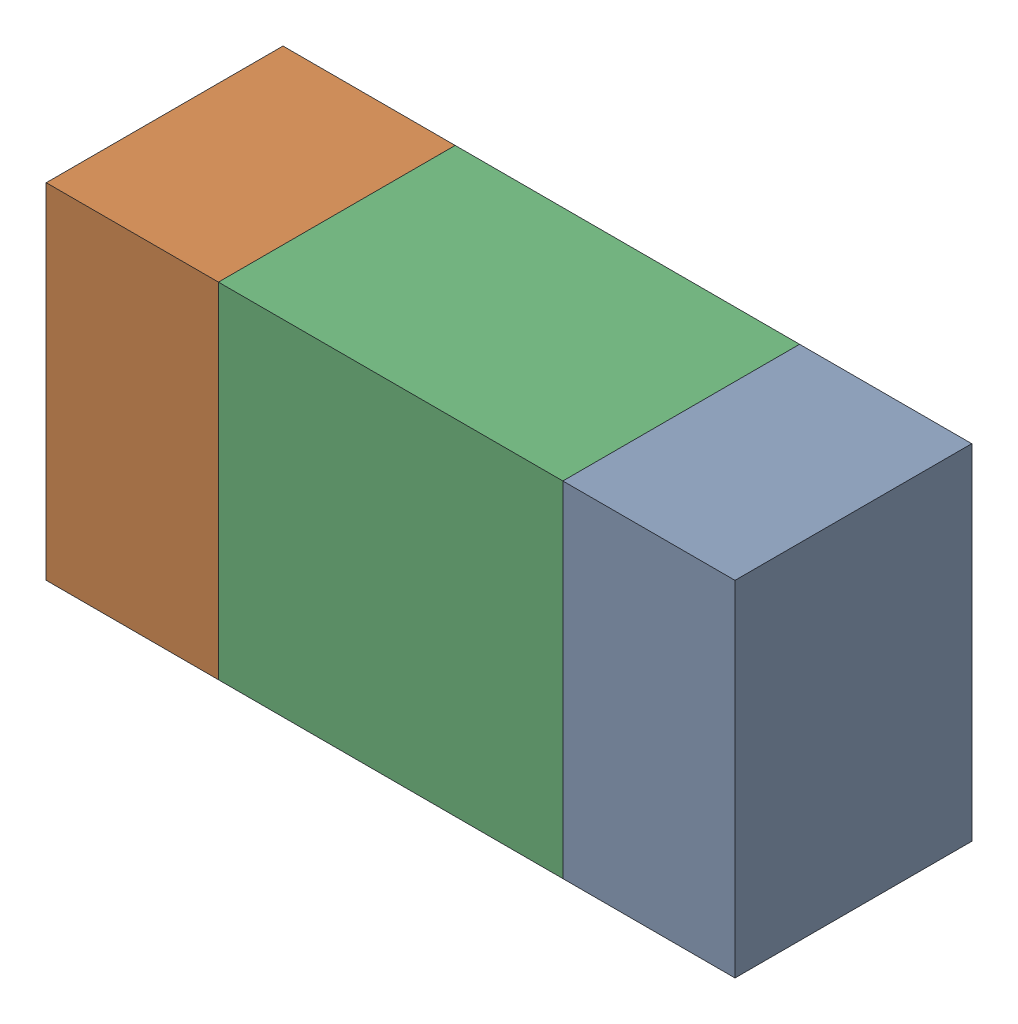
SolidWorks assembly R84, configuration ﾃﾞﾌｫﾙﾄ. Lengths in mm.
Overall size (1.6 0.8 0.55).
6 component instances, 2 part files, 0 mates.
Components (placement in the parent):
- 689261512-1: 689261512 [ﾃﾞﾌｫﾙﾄ] at (20.9199 17.4626 -1.7503) size (0.4 0.8 0.55)
  - Extruded_32-1: Extruded_32 [ﾃﾞﾌｫﾙﾄ] at origin size (0.4 0.8 0.55)
- 689261512-2: 689261512 [ﾃﾞﾌｫﾙﾄ] at (19.7199 17.4626 -1.7503) size (0.4 0.8 0.55)
  - Extruded_32-1: Extruded_32 [ﾃﾞﾌｫﾙﾄ] at origin size (0.4 0.8 0.55)
- 689261648-1: 689261648 [ﾃﾞﾌｫﾙﾄ] at (20.32 17.4626 -1.7503) size (0.8 0.8 0.55)
  - Extruded_33-1: Extruded_33 [ﾃﾞﾌｫﾙﾄ] at origin size (0.8 0.8 0.55)
